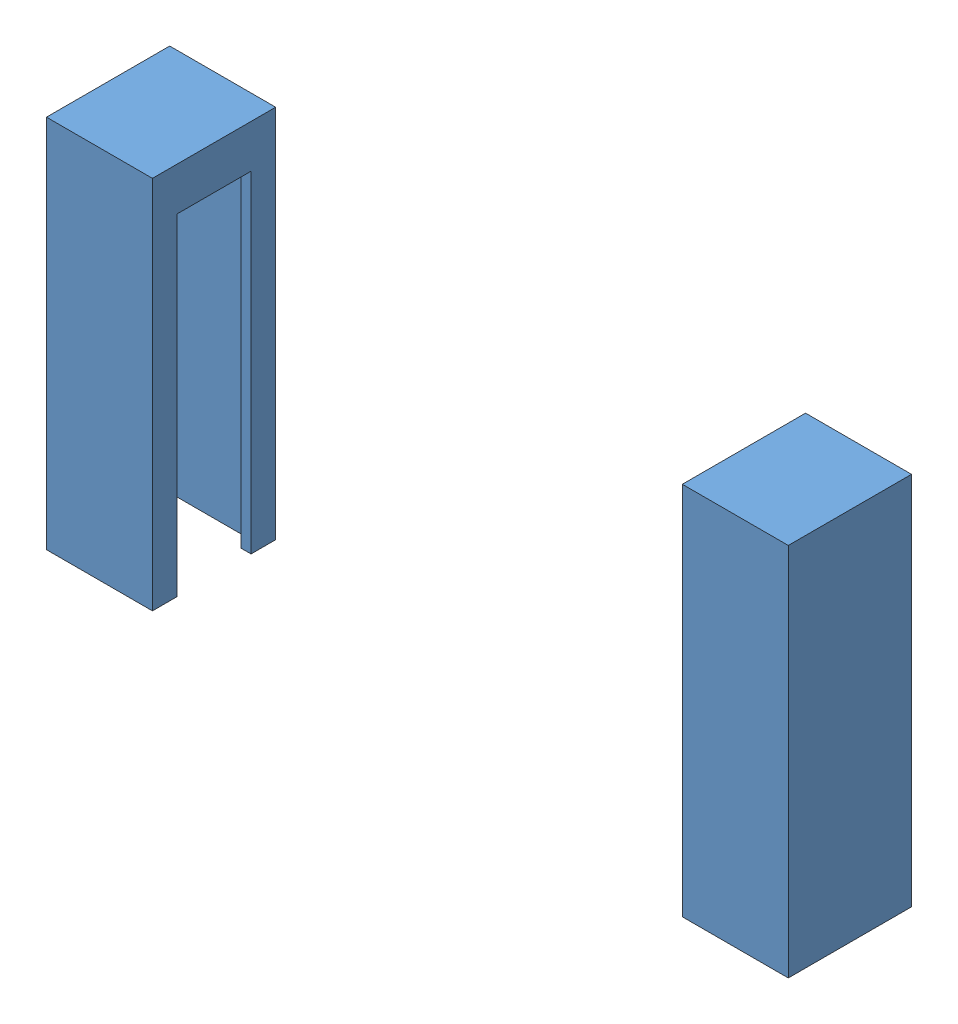
SolidWorks assembly preferenceV2_dispenser_IRAssembly - Copy, configuration Closer IRs. Lengths in mm.
Overall size (30.1 15.2 5).
4 component instances, 1 part files, 3 mates.
Components (placement in the parent):
- sparkfunIR_LEDandCase-1: sparkfunIR_LEDandCase [2Pin] at (-11.0025 21.2786 44.4241) x (-1 0 0) z (0 0 -1) size (4.3 15.2 5)
  - sparkfunIR_casing-1: sparkfunIR_casing [Default] at (-40.6525 -5.8286 32.4491) x (1 0 0) z (0 0 -1) size (4.3 15.2 5)
- sparkfunIR_LEDandCase-2: sparkfunIR_LEDandCase [3Pin] at (44.5025 21.2786 -20.4741) size (4.3 15.2 5)
  - sparkfunIR_casing-1: sparkfunIR_casing [Default] at (-40.6525 -5.8286 32.4491) x (1 0 0) z (0 0 -1) size (4.3 15.2 5)
Mates (geometry in assembly coordinates):
- Distance1: distance = 30.1 mm anti-aligned: plane of sparkfunIR_LEDandCase-2/sparkfunIR_casing-1 through (1.7 15.45 9.475) normal (-1 0 0); plane of sparkfunIR_LEDandCase-1/sparkfunIR_casing-1 through (31.8 15.45 14.475) normal (1 0 0)
- Coincident2: coincident aligned: plane of sparkfunIR_LEDandCase-1/sparkfunIR_casing-1 through (29.65 15.45 14.475) normal (0 0 1); plane of sparkfunIR_LEDandCase-2/sparkfunIR_casing-1 through (5.45 15.45 14.475) normal (0 0 1)
- Coincident3: coincident aligned: plane of sparkfunIR_LEDandCase-1/sparkfunIR_casing-1 through (31.8 0.25 14.475) normal (0 -1 0); plane of sparkfunIR_LEDandCase-2/sparkfunIR_casing-1 through (3.3 0.25 9.475) normal (0 -1 0)
